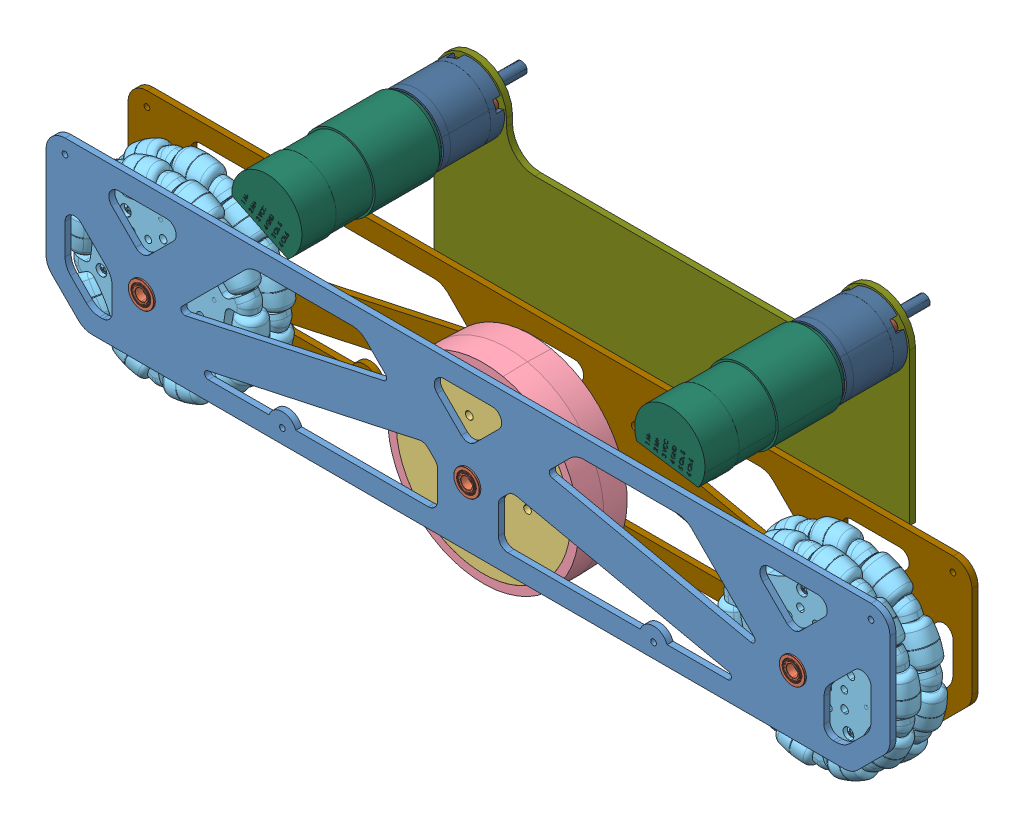
SolidWorks assembly Assembly, configuration Default. Lengths in mm.
Overall size (471.19 177.18 134.3).
43 component instances, 16 part files, 40 mates.
Components (placement in the parent):
- OuterSidePlate-1: OuterSidePlate [Default] at origin size (444.5 82.55 3.17)
- 535220.step-1: 535220.step [Default] at (50.8 31.75 -0.025) x (1 0 0) z (0 -1 0) size (13.5 4 13.5)
- 535220.step-2: 535220.step [Default] at (222.25 31.75 -0.025) x (0.577362 0.816488 0) z (0.816488 -0.577362 0) size (13.5 4 13.5)
- 535220.step-3: 535220.step [Default] at (393.7 31.75 -0.025) x (1 0 0) z (0 -1 0) size (13.5 4 13.5)
- am-2648_4inWheel8mmHub.STEP-1: am-2648_4inWheel8mmHub.STEP [Default] at (222.25 31.75 -18.8049) x (0 0 -1) z (0.978424 -0.206605 0) size (25.4 101.6 101.6)
  - 4in Wheel Intergreated Hub 8mm Rev2.STEP-1: 4in Wheel Intergreated Hub 8mm Rev2.STEP [Default] at origin size (25.4 92.71 92.71)
  - 4in Tread.STEP-1: 4in Tread.STEP [Default] at origin size (25.4 101.6 101.6)
- 595671 Part.step-1: 595671 Part.step [Default] at (393.7 31.75 -18.9933) x (0.993049 0.117703 0) z (0 0 1) size (99.71 101.47 14.61)
- 595671 Part.step-2: 595671 Part.step [Default] at (393.7 31.75 -4.8808) x (0.980818 -0.194926 0) z (0 0 1) size (99.71 101.47 14.61)
- 595671 Part.step-3: 595671 Part.step [Default] at (50.8 31.75 -4.8808) x (0.964902 0.262609 0) z (0 0 1) size (99.71 101.47 14.61)
- 595671 Part.step-4: 595671 Part.step [Default] at (50.8 31.75 -18.9933) x (0.836526 0.547927 0) z (0 0 1) size (99.71 101.47 14.61)
- 545618 assembly.step-1: 545618 assembly.step [Default] at (430.5068 26.5261 -16.838) x (0.987404 0.158221 0) z (-0.158221 0.987404 0) size (20.57 9.53 26.29)
  - 545618.step-1: 545618.step [Default] at (-35.5167 10.7278 10.9817) size (20.57 9.53 26.29)
  - 632110_90128A121.step-1: 632110_90128A121.step [Default] at (-40.2792 16.7603 -1.5913) x (0 0 1) z (-1 0 0) size (5.74 5.74 13.04)
- am-3443+6mmD+Single+Boss+Nub (1).step-1: am-3443+6mmD+Single+Boss+Nub (1).step [Default] at (239.278 18.9408 -52.793) x (0.545759 -0.837942 0) z (0 0 1) size (16 16 10)
- 545618 assembly.step-3: 545618 assembly.step [Default] at (84.0372 15.097 -16.838) x (0.986484 -0.163859 0) z (0.163859 0.986484 0) size (20.57 9.53 26.29)
  - 545618.step-1: 545618.step [Default] at (-35.5167 10.7278 10.9817) size (20.57 9.53 26.29)
  - 632110_90128A121.step-1: 632110_90128A121.step [Default] at (-40.2792 16.7603 -1.5913) x (0 0 1) z (-1 0 0) size (5.74 5.74 13.04)
- InnerSidePlate-1: InnerSidePlate [Default] at (0 0 -43.175) size (444.5 82.55 3.17)
- am-3637+NeveRest+20+Orbital+Gearmotor (2).STEP-1: am-3637+NeveRest+20+Orbital+Gearmotor (2).STEP [Default] at (148.4592 99.4337 -73.3569) x (0.943346 0.331812 0) z (0 0 -1) size (53.74 53.74 134.3)
  - NeveRest orbital 2 stage Gearbox.STEP-1: NeveRest orbital 2 stage Gearbox.STEP [Default] at (-28.8441 -12.442 -2.3383) size (36 36 59.11)
  - SHCS M3 x 16mm.STEP-1: SHCS M3 x 16mm.STEP [Default] at (-28.8441 1.8455 25.8811) size (5.5 5.5 19)
  - SHCS M3 x 16mm.STEP-2: SHCS M3 x 16mm.STEP [Default] at (-14.5566 -12.442 25.8811) x (0 -1 0) z (0 0 1) size (5.5 5.5 19)
  - SHCS M3 x 16mm.STEP-3: SHCS M3 x 16mm.STEP [Default] at (-28.8441 -26.7295 25.8811) x (-1 0 0) z (0 0 1) size (5.5 5.5 19)
  - SHCS M3 x 16mm.STEP-4: SHCS M3 x 16mm.STEP [Default] at (-43.1316 -12.442 25.8811) x (0 1 0) z (0 0 1) size (5.5 5.5 19)
  - 7804K117_STAINLESS STEEL BALL BEARING_7804K117.STEP-1: 7804K117_STAINLESS STEEL BALL BEARING_7804K117.STEP [Default] at (-28.8441 -12.442 28.7705) x (0.941717 0.336405 0) z (0 0 1) size (16 16 5)
  - 97633A150_BLACK-FINISH STEEL EXTERNAL RETAINING RING_97633A150_grv.STEP-1: 97633A150_BLACK-FINISH STEEL EXTERNAL RETAINING RING_97633A150_grv.STEP [Default] at (-28.8441 -12.442 31.715) x (0 0 -1) z (0.971339 -0.2377 0) size (0.64 10.57 9.01)
  - Shim.STEP-1: Shim.STEP [Default] at (-28.8441 -12.442 31.3975) x (1 0 0) z (0 1 0) size (12 0.13 12)
  - am-3104 NeveRest Motor.STEP-1: am-3104 NeveRest Motor.STEP [Default] at (-28.8441 -12.442 -2.3303) x (0.707107 0.707107 0) z (0 0 1) size (38 38 85.19)
- am-3637+NeveRest+20+Orbital+Gearmotor (2).STEP-2: am-3637+NeveRest+20+Orbital+Gearmotor (2).STEP [Default] at (359.9764 108.6773 -73.3569) x (0.805374 0.592767 0) z (0 0 -1) size (53.74 53.74 134.3)
  - NeveRest orbital 2 stage Gearbox.STEP-1: NeveRest orbital 2 stage Gearbox.STEP [Default] at (-28.8441 -12.442 -2.3383) size (36 36 59.11)
  - SHCS M3 x 16mm.STEP-1: SHCS M3 x 16mm.STEP [Default] at (-28.8441 1.8455 25.8811) size (5.5 5.5 19)
  - SHCS M3 x 16mm.STEP-2: SHCS M3 x 16mm.STEP [Default] at (-14.5566 -12.442 25.8811) x (0 -1 0) z (0 0 1) size (5.5 5.5 19)
  - SHCS M3 x 16mm.STEP-3: SHCS M3 x 16mm.STEP [Default] at (-28.8441 -26.7295 25.8811) x (-1 0 0) z (0 0 1) size (5.5 5.5 19)
  - SHCS M3 x 16mm.STEP-4: SHCS M3 x 16mm.STEP [Default] at (-43.1316 -12.442 25.8811) x (0 1 0) z (0 0 1) size (5.5 5.5 19)
  - 7804K117_STAINLESS STEEL BALL BEARING_7804K117.STEP-1: 7804K117_STAINLESS STEEL BALL BEARING_7804K117.STEP [Default] at (-28.8441 -12.442 28.7705) x (0.941717 0.336405 0) z (0 0 1) size (16 16 5)
  - 97633A150_BLACK-FINISH STEEL EXTERNAL RETAINING RING_97633A150_grv.STEP-1: 97633A150_BLACK-FINISH STEEL EXTERNAL RETAINING RING_97633A150_grv.STEP [Default] at (-28.8441 -12.442 31.715) x (0 0 -1) z (0.971339 -0.2377 0) size (0.64 10.57 9.01)
  - Shim.STEP-1: Shim.STEP [Default] at (-28.8441 -12.442 31.3975) x (1 0 0) z (0 1 0) size (12 0.13 12)
  - am-3104 NeveRest Motor.STEP-1: am-3104 NeveRest Motor.STEP [Default] at (-28.8441 -12.442 -2.3303) x (0.707107 0.707107 0) z (0 0 1) size (38 38 85.19)
- 535220.step-4: 535220.step [Default] at (50.8 31.75 -39.975) x (0.923728 0.383049 0) z (-0.383049 0.923728 0) size (13.5 4 13.5)
- 535220.step-5: 535220.step [Default] at (222.25 31.75 -39.975) x (0.923728 0.383049 0) z (-0.383049 0.923728 0) size (13.5 4 13.5)
- 535220.step-6: 535220.step [Default] at (393.7 31.75 -39.975) x (-0.330924 0.943658 0) z (-0.943658 -0.330924 0) size (13.5 4 13.5)
- InnermostPlate-3: InnermostPlate [Default] at (117.1208 101.6 -106.35) size (250.35 98.98 3.17)
Mates (geometry in assembly coordinates):
- Concentric1: concentric: cylinder of OuterSidePlate-1 through (50.8 31.75 3.175) axis (0 0 -1) radius 5.9996; cylinder of 535220.step-1 through (50.8 31.75 -0.025) axis (0 0 1) radius 3
- Coincident2: coincident: plane of OuterSidePlate-1 through (0 0 3.175) normal (0 0 1); plane of 535220.step-1 through (50.8 31.75 3.175) normal (0 0 -1)
- Concentric2: concentric: cylinder of OuterSidePlate-1 through (222.25 31.75 3.175) axis (0 0 -1) radius 6; cylinder of 535220.step-2 through (222.25 31.75 -0.025) axis (0 0 1) radius 3
- Concentric3: concentric: cylinder of OuterSidePlate-1 through (393.7 31.75 3.175) axis (0 0 -1) radius 5.9996; cylinder of 535220.step-3 through (393.7 31.75 -0.025) axis (0 0 1) radius 3
- Coincident5: coincident: plane of OuterSidePlate-1 through (0 0 3.175) normal (0 0 1); plane of 535220.step-3 through (393.7 31.75 3.175) normal (0 0 -1)
- Coincident6: coincident: plane of OuterSidePlate-1 through (0 0 3.175) normal (0 0 1); plane of 535220.step-2 through (222.25 31.75 3.175) normal (0 0 -1)
- Concentric4: concentric: cylinder of 535220.step-2 through (222.25 31.75 -0.025) axis (0 0 1) radius 3; cylinder of am-2648_4inWheel8mmHub.STEP-1/4in Wheel Intergreated Hub 8mm Rev2.STEP-1 through (222.25 31.75 -18.8049) axis (0 0 -1) radius 4
- Concentric6: concentric: cylinder of 595671 Part.step-1 through (393.7 31.75 -24.5496) axis (0 0 1) radius 6.35; cylinder of 595671 Part.step-2 through (393.7 31.75 -10.4371) axis (0 0 1) radius 6.35
- Distance1: distance = 3 mm: plane of 595671 Part.step-1 through (393.7 31.75 -18.9933) normal (0 0 1); plane of 595671 Part.step-2 through (393.7 31.75 -15.9933) normal (0 0 -1)
- Angle3: planar angle = 0.314159 rad: plane of 595671 Part.step-2 through (394.8959 21.6606 -4.8808) normal (-0.117703 0.993049 0); plane of 595671 Part.step-1 through (397.9551 22.524 -18.9933) normal (-0.418812 0.908073 0)
- Concentric7: concentric: cylinder of 535220.step-3 through (393.7 31.75 -0.025) axis (0 0 1) radius 3; cylinder of 595671 Part.step-2 through (393.7 31.75 -10.4371) axis (0 0 1) radius 6.35
- Distance2: distance = 3 mm: plane of 595671 Part.step-4 through (50.8 31.75 -18.9933) normal (0 0 1); plane of 595671 Part.step-3 through (50.8 31.75 -15.9933) normal (0 0 -1)
- Concentric8: concentric: cylinder of 595671 Part.step-3 through (50.8 31.75 -10.4371) axis (0 0 1) radius 6.35; cylinder of 595671 Part.step-4 through (50.8 31.75 -24.5496) axis (0 0 1) radius 6.35
- Angle4: planar angle = 0.314159 rad: plane of 595671 Part.step-3 through (56.3669 23.2509 -4.8808) normal (-0.547927 0.836526 0); plane of 595671 Part.step-4 through (58.7208 25.3872 -18.9933) normal (-0.779611 0.626264 0)
- Concentric9: concentric: cylinder of 535220.step-1 through (50.8 31.75 -0.025) axis (0 0 1) radius 3; cylinder of 595671 Part.step-3 through (50.8 31.75 -10.4371) axis (0 0 1) radius 6.35
- Coincident10: coincident: plane of am-2648_4inWheel8mmHub.STEP-1/4in Wheel Intergreated Hub 8mm Rev2.STEP-1 through (223.0764 35.6637 -4.8808) normal (0 0 1); plane of 595671 Part.step-2 through (393.7 31.75 -4.8808) normal (0 0 1)
- Parallel1: parallel: cylinder of 535220.step-2 through (222.25 31.75 -0.025) axis (0 0 1) radius 3; cylinder of am-2648_4inWheel8mmHub.STEP-1/4in Wheel Intergreated Hub 8mm Rev2.STEP-1 through (222.25 31.75 -18.8049) axis (0 0 -1) radius 4
- Coincident11: coincident: plane of am-2648_4inWheel8mmHub.STEP-1/4in Wheel Intergreated Hub 8mm Rev2.STEP-1 through (223.0764 35.6637 -4.8808) normal (0 0 1); plane of 595671 Part.step-3 through (50.8 31.75 -4.8808) normal (0 0 1)
- Coincident13: coincident: plane of 595671 Part.step-1 through (393.7 31.75 -30.1058) normal (0 0 -1); plane of 545618 assembly.step-1/545618.step-1 through (393.7 31.75 -30.1058) normal (0 0 1)
- Concentric11: concentric: cylinder of 595671 Part.step-1 through (393.7 31.75 -24.5496) axis (0 0 1) radius 6.35; cylinder of 545618 assembly.step-1/545618.step-1 through (393.7 31.75 -30.1058) axis (0 0 1) radius 6.35
- Tangent7: tangent: cylinder of 595671 Part.step-1 through (386.0194 37.8028 -24.5496) axis (0 0 1) radius 1.7526; curve of 545618 assembly.step-1/545618.step-1
- Concentric13: concentric: cylinder of am-2648_4inWheel8mmHub.STEP-1/4in Wheel Intergreated Hub 8mm Rev2.STEP-1 through (222.25 31.75 -18.8049) axis (0 0 -1) radius 4; cylinder of am-3443+6mmD+Single+Boss+Nub (1).step-1 through (222.25 31.75 -11.8808) axis (0 0 -1) radius 3
- Coincident14: coincident: plane of am-2648_4inWheel8mmHub.STEP-1/4in Wheel Intergreated Hub 8mm Rev2.STEP-1 through (223.0764 35.6637 -30.2808) normal (0 0 -1); plane of am-3443+6mmD+Single+Boss+Nub (1).step-1 through (226.4761 10.6028 -30.2808) normal (0 0 1)
- Concentric14: concentric: cylinder of am-2648_4inWheel8mmHub.STEP-1/4in Wheel Intergreated Hub 8mm Rev2.STEP-1 through (230.0774 30.0972 -4.8808) axis (0 0 -1) radius 1.75; cylinder of am-3443+6mmD+Single+Boss+Nub (1).step-1 through (230.0774 30.0972 -11.8808) axis (0 0 -1) radius 1.4859
- Concentric18: concentric: cylinder of 595671 Part.step-4 through (50.8 31.75 -24.5496) axis (0 0 1) radius 6.35; cylinder of 545618 assembly.step-3/545618.step-1 through (50.8 31.75 -27.5658) axis (0 0 1) radius 3
- Coincident18: coincident: plane of 595671 Part.step-4 through (50.8 31.75 -30.1058) normal (0 0 -1); plane of 545618 assembly.step-3/545618.step-1 through (50.8 31.75 -30.1058) normal (0 0 1)
- Tangent14: tangent: cylinder of 595671 Part.step-4 through (58.9804 37.1082 -24.5496) axis (0 0 1) radius 1.7526; curve of 545618 assembly.step-3/545618.step-1
- Distance3: distance = 40 mm: plane of InnerSidePlate-1 through (0 0 -40) normal (0 0 1); plane of OuterSidePlate-1 through (0 0 0) normal (0 0 -1)
- Coincident20: coincident: plane of OuterSidePlate-1 through (0 82.55 3.175) normal (0 1 0); plane of InnerSidePlate-1 through (0 82.55 -40) normal (0 1 0)
- Coincident21: coincident: plane of OuterSidePlate-1 through (444.5 0 3.175) normal (1 0 0); plane of InnerSidePlate-1 through (444.5 0 -40) normal (1 0 0)
- Concentric24: concentric: cylinder of InnerSidePlate-1 through (50.8 31.75 -40) axis (0 0 -1) radius 5.9996; cylinder of 535220.step-4 through (50.8 31.75 -43.175) axis (0 0 1) radius 6
- Coincident25: coincident: plane of InnerSidePlate-1 through (0 0 -43.175) normal (0 0 -1); plane of 535220.step-4 through (50.8 31.75 -43.175) normal (0 0 1)
- Concentric25: concentric: cylinder of InnerSidePlate-1 through (393.7 31.75 -40) axis (0 0 -1) radius 5.9996; cylinder of 535220.step-6 through (393.7 31.75 -43.175) axis (0 0 1) radius 6
- Coincident27: coincident: plane of InnerSidePlate-1 through (0 0 -43.175) normal (0 0 -1); plane of 535220.step-6 through (393.7 31.75 -43.175) normal (0 0 1)
- Concentric26: concentric: cylinder of InnerSidePlate-1 through (222.25 31.75 -40) axis (0 0 -1) radius 6; cylinder of 535220.step-5 through (222.25 31.75 -39.975) axis (0 0 -1) radius 3
- Coincident28: coincident: plane of InnerSidePlate-1 through (0 0 -43.175) normal (0 0 -1); plane of 535220.step-5 through (222.25 31.75 -43.175) normal (0 0 1)
- Distance5: distance = 60 mm: plane of InnerSidePlate-1 through (0 0 -43.175) normal (0 0 -1); plane of InnermostPlate-3 through (295.3208 97.55 -103.175) normal (0 0 1)
- Coincident36: coincident: plane of InnerSidePlate-1 through (0 82.55 -40) normal (0 1 0); plane of InnermostPlate-3 through (151.1708 82.55 -100.326) normal (0 1 0)
- Coincident42: coincident: plane of am-3637+NeveRest+20+Orbital+Gearmotor (2).STEP-2/NeveRest orbital 2 stage Gearbox.STEP-1 through (329.3708 101.6 -100.326) normal (0 0 -1); plane of InnermostPlate-3 through (295.3208 97.55 -100.326) normal (0 0 1)
- Coincident43: coincident: plane of am-3637+NeveRest+20+Orbital+Gearmotor (2).STEP-1/NeveRest orbital 2 stage Gearbox.STEP-1 through (117.1208 101.6 -100.326) normal (0 0 -1); plane of InnermostPlate-3 through (295.3208 97.55 -100.326) normal (0 0 1)
